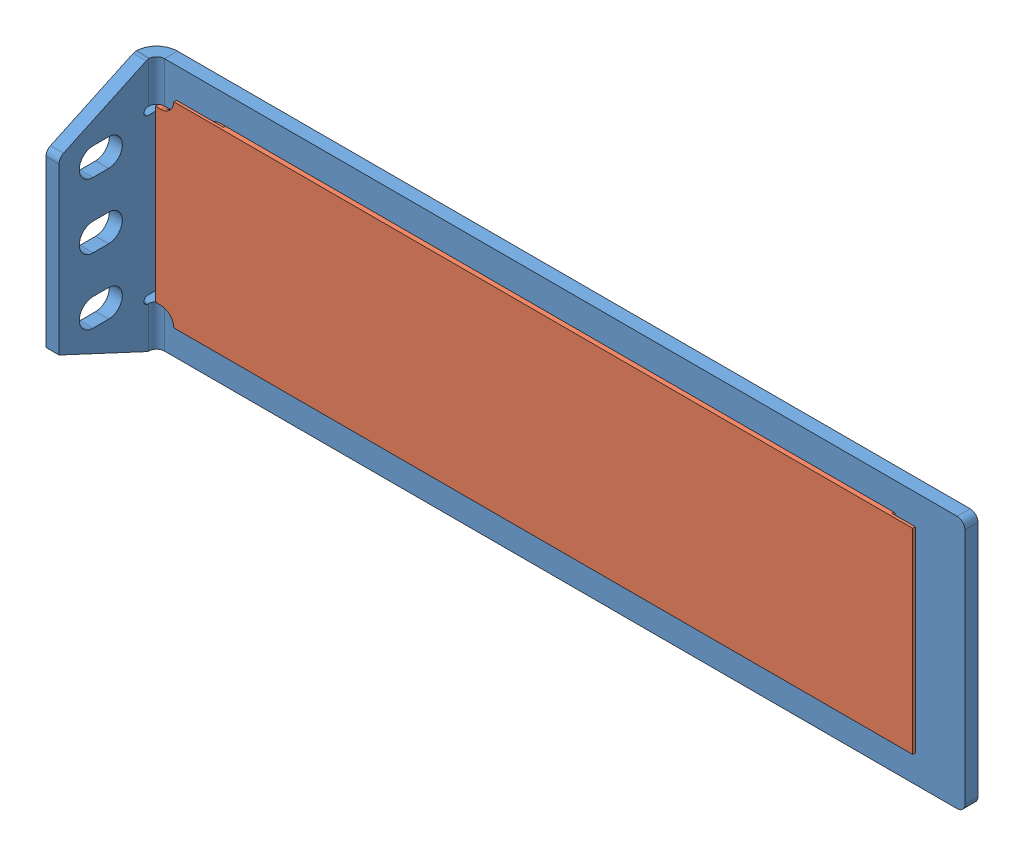
SolidWorks assembly Glideklods_5_GBR_kpl, configuration Default. Lengths in mm.
Overall size (314.61 97.01 45.35).
2 component instances, 2 part files, 3 mates.
Components (placement in the parent):
- 6300366-2: 6300366 [Default] at (139.7404 -69.7334 27.8151) size (314.61 97.01 42.5)
- 63760-1: 63760 [6299054] at (-169.2596 15.7666 28.8151) x (1 0 0) z (0 0 -1) size (290 75 9)
Mates (geometry in assembly coordinates):
- Distance1: distance = 0 mm anti-aligned: plane of 63760-1 through (-169.2596 15.7666 27.8151) normal (0 0 -1); plane of 6300366-2 through (136.7404 24.2666 27.8151) normal (0 0 1)
- Distance3: distance = 0 mm anti-aligned: plane of 63760-1 through (120.7404 15.7666 19.8151) normal (1 0 0); plane of 6300366-2 through (120.7404 -50.5692 22.8151) normal (-1 0 0)
- Distance4: distance = 0.25 mm anti-aligned: plane of 63760-1 through (-162.2596 -59.2334 19.8151) normal (0 -1 0); plane of 6300366-2 through (112.3262 -58.9834 22.8151) normal (0 1 0)
